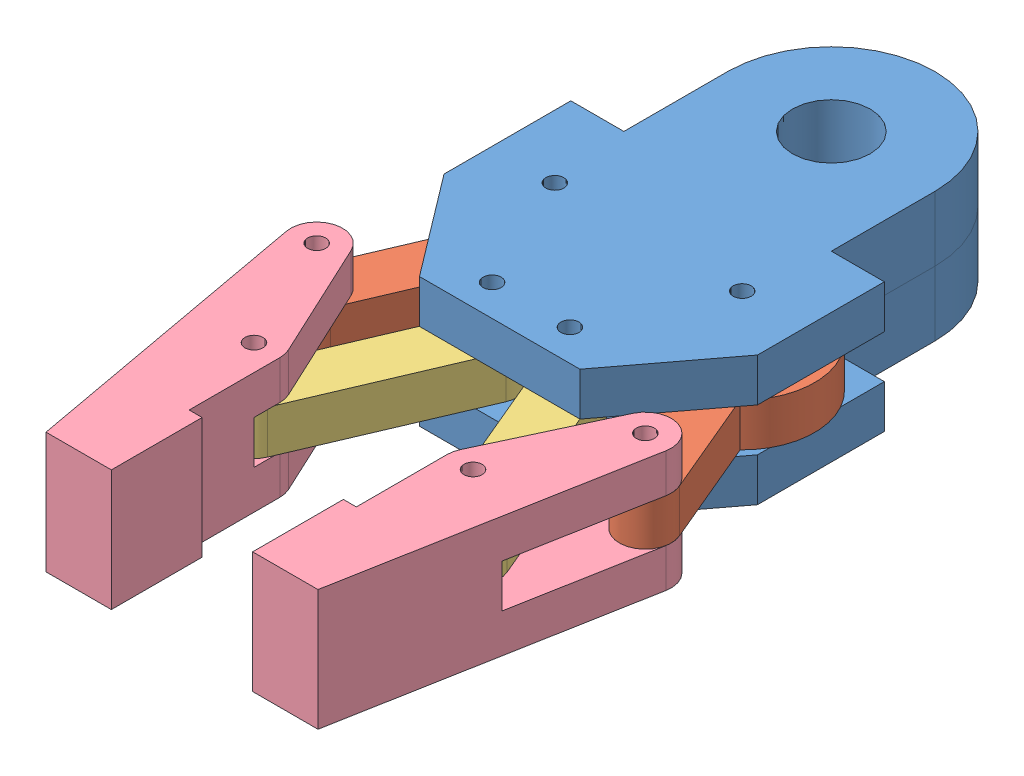
SolidWorks assembly grip, configuration Default. Lengths in mm.
Overall size (93.02 25 145.17).
8 component instances, 4 part files, 19 mates.
Components (placement in the parent):
- g1-1: g1 [Default] at (25.017 22.4417 88.248) size (60.45 12.5 83.94)
- g2-1: g2 [Default] at (6.9516 30.7751 65.5903) x (-0.392119 0 0.919915) z (0 1 0) size (53.95 27.9 8.33)
- g3-1: g3 [Default] at (46.0944 30.7751 120.5072) x (-0.387923 0 -0.921692) z (0 1 0) size (45 10 8.33)
- g4-1: g4 [Default] at (46.0944 46.6084 120.5072) x (-1 0 0) z (0 -1 0) size (23.07 62.66 23.33)
- g2-2: g2 [Default] at (43.0825 30.7751 65.5903) x (0.387923 0 0.921692) z (0 1 0) size (53.95 27.9 8.33)
- g3-2: g3 [Default] at (3.7929 30.7751 120.445) x (0.392119 0 -0.919915) z (0 1 0) size (45 10 8.33)
- g4-2: g4 [Default] at (3.7929 23.2751 120.445) x (1 0 0) z (0 1 0) size (23.07 62.66 23.33)
- g1-2: g1 [Default] at (25.017 47.4417 88.248) x (-1 0 0) z (0 0 1) size (60.45 12.5 83.94)
Mates (geometry in assembly coordinates):
- Coincident2: coincident: plane of g1-1 through (25.017 30.7751 88.248) normal (0 1 0); plane of g2-1 through (-6.7726 30.7751 97.7874) normal (0 -1 0)
- Coincident3: coincident: plane of g1-1 through (25.017 30.7751 88.248) normal (0 1 0); plane of g2-2 through (56.6598 30.7751 97.8495) normal (0 -1 0)
- Coincident4: coincident: plane of g1-1 through (25.017 30.7751 88.248) normal (0 1 0); plane of g3-1 through (46.0944 30.7751 120.5072) normal (0 -1 0)
- Coincident5: coincident: plane of g1-1 through (25.017 30.7751 88.248) normal (0 1 0); plane of g3-2 through (3.7929 30.7751 120.445) normal (0 -1 0)
- Concentric1: concentric: cylinder of g1-1 through (32.517 30.7751 88.248) axis (0 -1 0) radius 1.75; cylinder of g3-1 through (32.517 39.1084 88.248) axis (0 -1 0) radius 1.75
- Concentric2: concentric: cylinder of g1-1 through (17.517 30.7751 88.248) axis (0 -1 0) radius 1.75; cylinder of g3-2 through (17.517 39.1084 88.248) axis (0 -1 0) radius 1.75
- Concentric3: concentric: cylinder of g1-1 through (43.0825 30.7751 65.5903) axis (0 -1 0) radius 1.75; cylinder of g2-2 through (43.0825 39.1084 65.5903) axis (0 -1 0) radius 1.75
- Concentric4: concentric: cylinder of g1-1 through (6.9516 30.7751 65.5903) axis (0 -1 0) radius 1.75; cylinder of g2-1 through (6.9516 39.1084 65.5903) axis (0 -1 0) radius 1.75
- Coincident6: coincident: plane of g3-2 through (3.7929 39.1084 120.445) normal (0 1 0); plane of g4-2 through (3.7929 39.1084 120.445) normal (0 -1 0)
- Concentric5: concentric: cylinder of g3-2 through (3.7929 39.1084 120.445) axis (0 -1 0) radius 1.75; cylinder of g4-2 through (3.7929 46.6084 120.445) axis (0 -1 0) radius 1.75
- Concentric6: concentric: cylinder of g2-1 through (-6.7726 39.1084 97.7874) axis (0 -1 0) radius 1.75; cylinder of g4-2 through (-6.7726 46.6084 97.7874) axis (0 -1 0) radius 1.75
- Coincident7: coincident: plane of g4-1 through (46.0944 30.7751 120.5072) normal (0 1 0); plane of g2-2 through (56.6598 30.7751 97.8495) normal (0 -1 0)
- Concentric7: concentric: cylinder of g4-1 through (56.6598 39.1084 97.8495) axis (0 1 0) radius 1.75; cylinder of g2-2 through (56.6598 39.1084 97.8495) axis (0 -1 0) radius 1.75
- Concentric8: concentric: cylinder of g3-1 through (46.0944 39.1084 120.5072) axis (0 -1 0) radius 1.75; cylinder of g4-1 through (46.0944 39.1084 120.5072) axis (0 1 0) radius 1.75
- Concentric9: concentric: cylinder of g1-1 through (25.017 34.9417 30.3403) axis (0 -1 0) radius 7.5; cylinder of g1-2 through (25.017 34.9417 30.3403) axis (0 1 0) radius 7.5
- Coincident9: coincident: plane of g1-1 through (25.017 34.9417 30.3403) normal (0 1 0); plane of g1-2 through (25.017 34.9417 30.3403) normal (0 -1 0)
- Concentric10: concentric: cylinder of g2-1 through (6.9516 39.1084 65.5903) axis (0 -1 0) radius 1.75; cylinder of g1-2 through (6.9516 39.1084 65.5903) axis (0 1 0) radius 1.75
- Concentric11: concentric: cylinder of g3-2 through (17.517 39.1084 88.248) axis (0 -1 0) radius 1.75; cylinder of g1-2 through (17.517 39.1084 88.248) axis (0 1 0) radius 1.75
- GearMate1: gear = 3.5 : 3.5 mm: circle of g2-1; circle of g2-2
